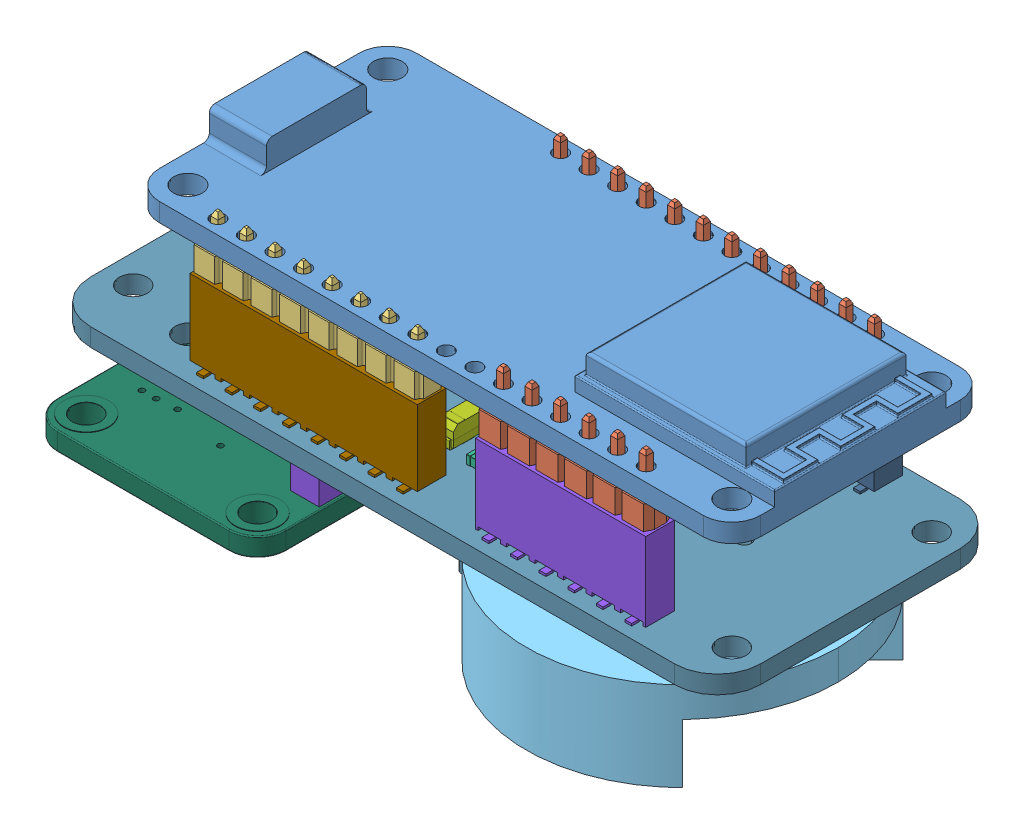
SolidWorks assembly RevB_Electrical_Assembly, configuration Default. Lengths in mm.
Overall size (60.61 27.58 27.76).
51 component instances, 15 part files, 20 mates.
Components (placement in the parent):
- Adafruit M0 AT1500 Feather_000-1: Adafruit M0 AT1500 Feather_000 [Default] at (11.6006 27.5935 45.6601) size (53.47 4.7 22.86)
- 68001-x06-1: 68001-x06 [Default] at (29.4441 27.3903 55.8201) x (-1 0 0) z (0 0 1) size (15.24 11.43 2.41)
- 68001-x06-2: 68001-x06 [Default] at (1.5041 27.3903 35.5001) x (1 0 0) z (0 0 -1) size (15.24 11.43 2.41)
- 68001-x06-3: 68001-x06 [Default] at (16.7441 27.3903 35.5001) x (1 0 0) z (0 0 -1) size (15.24 11.43 2.41)
- p10129378-x08002blf-1: p10129378-x08002blf [Default] at (-8.6559 27.3935 55.8201) x (0 -1 0) z (0 0 -1) size (10.67 20.32 2.41)
- p21014-1: p21014 [Default] at (-188.4959 16.2035 -14.4999) x (1 0 0) z (0 1 0) size (59.61 27.76 20.34)
  - p21014.step-1: p21014.step [Default] at origin size (59.61 27.76 20.34)
    - LED_0805_2012Metric.step-1: LED_0805_2012Metric.step [Default] at (193.91 -69.95 -0.05) x (1 0 0) z (0 0 -1) size (2 1.25 1.1)
      - SOLID.step-1: SOLID.step [Default] at origin size (2 1.25 1.1)
    - keystone-PN1027.step-1: keystone-PN1027.step [Default] at (211 -60.16 -2.55) x (0 1 0) z (-1 0 0) size (27.76 16.03 30.96)
      - SOLID-0.step-1: SOLID-0.step [Default] at origin size (27.76 16.03 30.96)
    - C_0603_1608Metric.step-1: C_0603_1608Metric.step [Default] at (203.265 -66.415 1.65) size (1.6 0.8 0.8)
      - SOLID-1.step-1: SOLID-1.step [Default] at origin size (1.6 0.8 0.8)
    - C_0603_1608Metric.step-2: C_0603_1608Metric.step [Default] at (203.365 -63.405 1.65) size (1.6 0.8 0.8)
      - SOLID-1.step-1: SOLID-1.step [Default] at origin size (1.6 0.8 0.8)
    - C_0603_1608Metric.step-3: C_0603_1608Metric.step [Default] at (199.255 -66.415 1.65) size (1.6 0.8 0.8)
      - SOLID-1.step-1: SOLID-1.step [Default] at origin size (1.6 0.8 0.8)
    - C_0603_1608Metric.step-4: C_0603_1608Metric.step [Default] at (199.355 -63.405 1.65) size (1.6 0.8 0.8)
      - SOLID-1.step-1: SOLID-1.step [Default] at origin size (1.6 0.8 0.8)
    - CP_EIA-3216-18_Kemet-A.step-1: CP_EIA-3216-18_Kemet-A.step [Default] at (196.02 -64.89 1.65) x (0 1 0) z (0 0 1) size (3.2 1.6 1.8)
      - SOLID-2.step-1: SOLID-2.step [Default] at origin size (3.2 1.6 1.8)
    - LED_0805_2012Metric.step-2: LED_0805_2012Metric.step [Default] at (190.44 -70.04 -0.05) x (0 1 0) z (0 0 -1) size (2 1.25 1.1)
      - SOLID.step-1: SOLID.step [Default] at origin size (2 1.25 1.1)
    - 91601-306LFc.step-1: 91601-306LFc.step [Default] at (185 -60.16 -7.25) x (0 -1 0) z (1 0 0) size (15.16 7.2 3.19)
      - SOLID-3.step-1: SOLID-3.step [Default] at origin size (15.16 7.2 3.19)
    - 91601-308LFc.step-1: 91601-308LFc.step [Default] at (188.73 -70.32 8.85) x (1 0 0) z (0 -1 0) size (20.24 7.2 3.19)
      - SOLID-4.step-1: SOLID-4.step [Default] at origin size (20.24 7.2 3.19)
    - 91601-412ALFc.step-1: 91601-412ALFc.step [Default] at (203.97 -50 8.85) x (1 0 0) z (0 -1 0) size (30.4 7.2 3.19)
      - SOLID-5.step-1: SOLID-5.step [Default] at origin size (30.4 7.2 3.19)
    - 91601-306LFc.step-2: 91601-306LFc.step [Default] at (211.59 -70.32 8.85) x (1 0 0) z (0 -1 0) size (15.16 7.2 3.19)
      - SOLID-3.step-1: SOLID-3.step [Default] at origin size (15.16 7.2 3.19)
    - R_0603_1608Metric.step-1: R_0603_1608Metric.step [Default] at (198.265 -58.125 1.65) x (0 1 0) z (0 0 1) size (1.6 0.8 0.45)
      - SOLID-6.step-1: SOLID-6.step [Default] at origin size (1.6 0.8 0.45)
    - R_0603_1608Metric.step-2: R_0603_1608Metric.step [Default] at (195.165 -54.115 1.65) x (0 1 0) z (0 0 1) size (1.6 0.8 0.45)
      - SOLID-6.step-1: SOLID-6.step [Default] at origin size (1.6 0.8 0.45)
    - R_0603_1608Metric.step-3: R_0603_1608Metric.step [Default] at (204.21 -54.11 1.65) x (0 1 0) z (0 0 1) size (1.6 0.8 0.45)
      - SOLID-6.step-1: SOLID-6.step [Default] at origin size (1.6 0.8 0.45)
    - R_0603_1608Metric.step-4: R_0603_1608Metric.step [Default] at (201.27 -58.12 1.65) x (0 1 0) z (0 0 1) size (1.6 0.8 0.45)
      - SOLID-6.step-1: SOLID-6.step [Default] at origin size (1.6 0.8 0.45)
    - R_0603_1608Metric.step-5: R_0603_1608Metric.step [Default] at (201.27 -54.09 1.65) x (0 1 0) z (0 0 1) size (1.6 0.8 0.45)
      - SOLID-6.step-1: SOLID-6.step [Default] at origin size (1.6 0.8 0.45)
    - R_0603_1608Metric.step-6: R_0603_1608Metric.step [Default] at (198.265 -54.115 1.65) x (0 1 0) z (0 0 1) size (1.6 0.8 0.45)
      - SOLID-6.step-1: SOLID-6.step [Default] at origin size (1.6 0.8 0.45)
    - R_0603_1608Metric.step-7: R_0603_1608Metric.step [Default] at (204.21 -58.135 1.65) x (0 1 0) z (0 0 1) size (1.6 0.8 0.45)
      - SOLID-6.step-1: SOLID-6.step [Default] at origin size (1.6 0.8 0.45)
    - CP_EIA-6032-15_Kemet-U.step-1: CP_EIA-6032-15_Kemet-U.step [Default] at (192.7 -49.67 -0.05) x (1 0 0) z (0 0 -1) size (6.3 3.5 1.5)
      - SOLID-7.step-1: SOLID-7.step [Default] at origin size (6.3 3.5 1.5)
    - SOT-223.step-1: SOT-223.step [Default] at (208.64 -60.08 1.65) x (0 1 0) z (0 0 1) size (7 6.5 1.7)
      - SOLID-8.step-1: SOLID-8.step [Default] at origin size (7 6.5 1.7)
    - COMPOUND.step-1: COMPOUND.step [Default] at origin size (59.61 25.4 1.6)
- Adafruit_BNO055-1: Adafruit_BNO055 [Default] at (-1.9559 8.9535 32.3251) x (0 0 1) z (1 0 0) size (26.67 4.2 20.32)
Mates (geometry in assembly coordinates):
- Coincident2: coincident: plane of Adafruit M0 AT1500 Feather_000-1 through (35.7941 27.5935 54.5501) normal (0 -1 0); plane of 68001-x06-1 through (28.7837 27.5935 56.3789) normal (0 1 0)
- Coincident3: coincident anti-aligned: plane of Adafruit M0 AT1500 Feather_000-1 through (35.7941 27.5935 54.5501) normal (0 -1 0); plane of p10129378-x08002blf-1 through (-6.7759 27.5935 55.2601) normal (0 1 0)
- Width3: width anti-aligned: plane of p10129378-x08002blf-1 through (-8.6559 28.4241 55.5001) normal (0 0 -1); plane of p10129378-x08002blf-1 through (-8.6559 28.4241 56.1401) normal (0 0 1)
- Width5: width aligned: plane of 68001-x06-3 through (29.4441 24.9265 35.8176) normal (0 0 1); plane of 68001-x06-3 through (29.4441 24.9265 35.1826) normal (0 0 -1)
- Width6: width aligned: plane of 68001-x06-2 through (1.5041 24.9265 35.8176) normal (0 0 1); plane of 68001-x06-2 through (1.5041 24.9265 35.1826) normal (0 0 -1)
- Coincident4: coincident anti-aligned: plane of Adafruit M0 AT1500 Feather_000-1 through (35.7941 27.5935 54.5501) normal (0 -1 0); plane of 68001-x06-3 through (16.0837 27.5935 36.0589) normal (0 1 0)
- Coincident5: coincident anti-aligned: plane of Adafruit M0 AT1500 Feather_000-1 through (35.7941 27.5935 54.5501) normal (0 -1 0); plane of 68001-x06-2 through (13.5437 27.5935 36.0589) normal (0 1 0)
- Width7: width aligned: plane of 68001-x06-3 through (29.7616 24.9265 35.5001) normal (1 0 0); plane of 68001-x06-3 through (29.1266 24.9265 35.5001) normal (-1 0 0)
- Width8: width anti-aligned: plane of 68001-x06-2 through (14.5216 24.9265 35.5001) normal (1 0 0); plane of 68001-x06-2 through (13.8866 24.9265 35.5001) normal (-1 0 0)
- Width9: width aligned: plane of p10129378-x08002blf-1 through (-8.3359 28.4241 55.8201) normal (1 0 0); plane of p10129378-x08002blf-1 through (-8.9759 28.4241 55.8201) normal (-1 0 0)
- Width10: width aligned: plane of 68001-x06-1 through (29.4441 24.9265 56.1376) normal (0 0 1); plane of 68001-x06-1 through (29.4441 24.9265 55.5026) normal (0 0 -1)
- Width11: width anti-aligned: plane of 68001-x06-1 through (29.7616 24.9265 55.8201) normal (1 0 0); plane of 68001-x06-1 through (29.1266 24.9265 55.8201) normal (-1 0 0)
- Concentric1: concentric anti-aligned: cylinder of Adafruit M0 AT1500 Feather_000-1 through (35.7941 29.2445 54.5501) axis (0 -1 0) radius 1.27; cylinder of p21014-1/p21014.step-1/COMPOUND.step-1 through (35.7941 15.4035 54.5501) axis (0 1 0) radius 1.25
- Coincident6: coincident aligned: plane of Adafruit M0 AT1500 Feather_000-1 through (38.3341 29.2445 54.5501) normal (1 0 0); plane of p21014-1/p21014.step-1/COMPOUND.step-1 through (38.3341 16.2035 36.7701) normal (1 0 0)
- Coincident7: coincident anti-aligned: plane of 68001-x06-3 through (30.1045 25.0535 34.9413) normal (0 -1 0); plane of p21014-1/p21014.step-1/91601-412ALFc.step-1/SOLID-5.step-1 through (15.4741 25.0535 35.5001) normal (0 1 0)
- Concentric2: concentric aligned: cylinder of p21014-1/p21014.step-1/COMPOUND.step-1 through (-18.7359 15.4035 38.0401) axis (0 1 0) radius 1.25; cylinder of Adafruit_BNO055-1 through (-40.004 7.3035 34.8651) axis (0 1 0) radius 1.25
- Parallel1: parallel aligned: plane of p21014-1/p21014.step-1/COMPOUND.step-1 through (-21.2759 16.2035 54.5501) normal (-1 0 0); plane of Adafruit_BNO055-1 through (-22.2759 7.3035 34.8651) normal (-1 0 0)
- Width12: width aligned: plane of Adafruit_BNO055-1 through (-4.4959 7.3035 32.3251) normal (0 0 -1); plane of p21014-1/p21014.step-1/COMPOUND.step-1 through (-4.4959 7.3035 58.9951) normal (0 0 1); plane of Adafruit_BNO055-1 through (-17.4659 16.2035 32.9601) normal (0 0 -1); plane of p21014-1/p21014.step-1/COMPOUND.step-1 through (34.5241 16.2035 58.3601) normal (0 0 1)
- Coincident8: coincident anti-aligned: plane of p21014-1/p21014.step-1/91601-306LFc.step-1/SOLID-3.step-1 through (-3.4959 8.9535 45.6601) normal (0 -1 0); plane of Adafruit_BNO055-1 through (-4.4959 8.9535 56.4551) normal (0 1 0)
- Tangent3: tangent aligned: cylinder of Adafruit_BNO055-1 through (-3.2259 7.3035 41.8501) axis (0 1 0) radius 0.5
